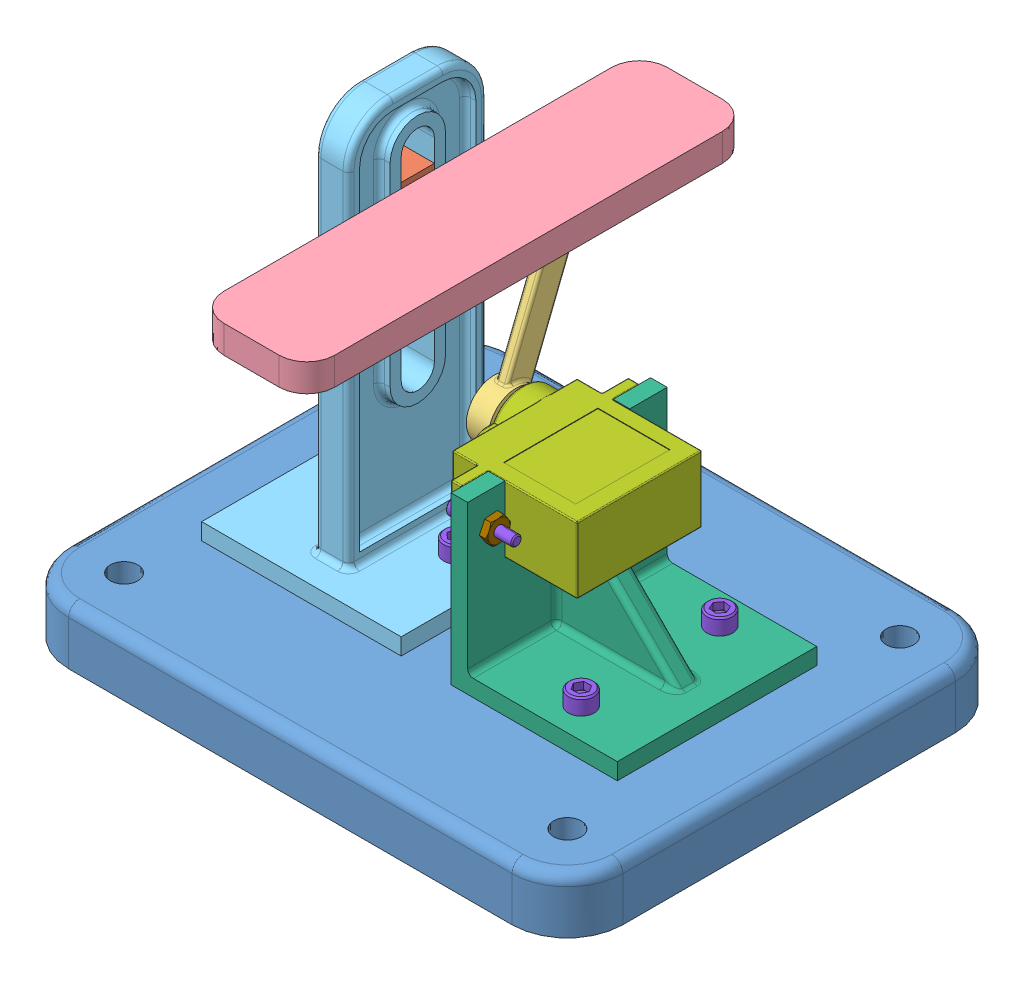
SolidWorks assembly motion_study, configuration Default. Lengths in mm.
Overall size (100 83 80).
20 component instances, 9 part files, 43 mates.
Components (placement in the parent):
- base-1: base [Default] at (53.4637 35.5858 76.1242) size (100 10 80)
- clip-1: clip [Default] at (28.4637 101.0884 76.1242) x (0 0 1) z (0 1 0) size (10 8 7)
- servo_arm-1: servo_arm [Default] at (46.9637 83.5225 65.3271) x (0 -0.929109 0.369805) z (0 -0.369805 -0.929109) size (38 4 10)
- shelf-1: shelf [Default] at (46.4637 98.5884 76.1242) x (0 0 -1) z (1 0 0) size (80 5 26)
- bracket-1: bracket [Default] at (33.4637 45.5858 76.1242) size (36 73 36)
- servo_mount-1: servo_mount [Default] at (60.4637 45.5858 76.1242) x (-1 0 0) z (0 -1 0) size (30 36 30)
- Micro Servo SG92R 180-1: Micro Servo SG92R 180 [Valor predeterminado] at (60.4637 69.5858 76.1242) x (0 0 1) z (0 -1 0) size (32 29 12)
- socket head cap screw_ai-1: socket head cap screw_ai [HX-SHCS 0.112-40x0.375x0.375-N] at (78.4637 51.4306 63.6242) x (0 -1 0) z (-0.79632 0 -0.604876) size (12.37 4.65 4.65)
- socket head cap screw_ai-2: socket head cap screw_ai [HX-SHCS 0.112-40x0.375x0.375-N] at (43.4637 51.4306 76.1242) x (0 -1 0) z (-0.276776 0 -0.960934) size (12.37 4.65 4.65)
- socket head cap screw_ai-3: socket head cap screw_ai [HX-SHCS 0.112-40x0.375x0.375-N] at (78.4637 51.4306 88.6242) x (0 -1 0) z (-0.041603 0 -0.999134) size (12.37 4.65 4.65)
- socket head cap screw_ai-4: socket head cap screw_ai [HX-SHCS 0.112-40x0.375x0.375-N] at (23.4637 51.4306 76.1242) x (0 -1 0) z (0.675067 0 0.737757) size (12.37 4.65 4.65)
- socket head cap screw_ai-5: socket head cap screw_ai [HX-SHCS 0.112-40x0.375x0.375-N] at (25.6189 101.0884 76.1242) x (1 0 0) z (0 0.700306 0.713843) size (12.37 4.65 4.65)
- machine screw nut hex_ai-1: machine screw nut hex_ai [MSHXNUT 0.112-40-S-N] at (23.4637 41.0966 76.1242) x (-0.51199 0 0.858991) z (0 -1 0) size (6.35 7.33 2.49)
- machine screw nut hex_ai-2: machine screw nut hex_ai [MSHXNUT 0.112-40-S-N] at (43.4637 43.5858 76.1242) x (-0.141311 0 -0.989965) z (0 1 0) size (6.35 7.33 2.49)
- machine screw nut hex_ai-3: machine screw nut hex_ai [MSHXNUT 0.112-40-S-N] at (78.4637 43.5858 88.6242) x (-0.491759 0 -0.870731) z (0 1 0) size (6.35 7.33 2.49)
- machine screw nut hex_ai-5: machine screw nut hex_ai [MSHXNUT 0.112-40-S-N] at (78.4637 43.5858 63.6242) x (-0.341325 0 -0.939945) z (0 1 0) size (6.35 7.33 2.49)
- machine screw nut hex_ai-6: machine screw nut hex_ai [MSHXNUT 0.073-72-S-N] at (64.7337 69.5858 89.7492) x (0 -0.430699 -0.902496) z (1 0 0) size (3.96 4.58 1.27)
- machine screw nut hex_ai-7: machine screw nut hex_ai [MSHXNUT 0.073-72-S-N] at (64.7337 69.5858 62.4992) x (0 0.064997 -0.997885) z (1 0 0) size (3.96 4.58 1.27)
- socket head cap screw_ai-7: socket head cap screw_ai [HX-SHCS 0.073-72x0.375x0.375-N] at (56.6095 69.5858 62.4992) x (1 0 0) z (0 -0.009409 0.999956) size (11.38 3 3)
- socket head cap screw_ai-8: socket head cap screw_ai [HX-SHCS 0.073-72x0.375x0.375-N] at (56.6095 69.5858 89.7492) size (11.38 3 3)
Mates (geometry in assembly coordinates):
- Coincident1: coincident anti-aligned: plane of base-1 through (53.4637 45.5858 76.1242) normal (0 1 0); plane of bracket-1 through (33.4637 45.5858 76.1242) normal (0 -1 0)
- Concentric1: concentric aligned: circle of base-1; circle of bracket-1
- Concentric2: concentric aligned: circle of base-1; circle of bracket-1
- Coincident4: coincident anti-aligned: plane of shelf-1 through (30.4637 98.5884 79.1242) normal (0 0 1); plane of bracket-1 through (-33.5363 108.5858 79.1242) normal (0 0 -1)
- Coincident5: coincident anti-aligned: plane of shelf-1 through (36.4637 103.5884 36.1242) normal (-1 0 0); plane of bracket-1 through (36.4637 118.5858 88.6242) normal (1 0 0)
- Coincident6: coincident anti-aligned: plane of clip-1 through (36.4637 103.5884 79.1242) normal (0 -1 0); plane of shelf-1 through (46.4637 103.5884 76.1242) normal (0 1 0)
- Concentric3: concentric anti-aligned: circle of clip-1; circle of shelf-1
- Coincident8: coincident anti-aligned: plane of clip-1 through (30.4637 101.0884 76.1242) normal (1 0 0); plane of bracket-1 through (30.4637 118.5858 88.6242) normal (-1 0 0)
- Coincident11: coincident anti-aligned: plane of base-1 through (53.4637 45.5858 76.1242) normal (0 1 0); plane of servo_mount-1 through (60.4637 45.5858 58.1242) normal (0 -1 0)
- Concentric8: concentric aligned: circle of base-1; circle of servo_mount-1
- Concentric9: concentric aligned: circle of base-1; circle of servo_mount-1
- Coincident14: coincident anti-aligned: plane of servo_mount-1 through (60.4637 45.5858 58.1242) normal (-1 0 0); plane of Micro Servo SG92R 180-1 through (60.4637 69.5858 89.7492) normal (1 0 0)
- Concentric10: concentric anti-aligned: circle of servo_mount-1; circle of Micro Servo SG92R 180-1
- Concentric11: concentric anti-aligned: circle of servo_mount-1; circle of Micro Servo SG92R 180-1
- Concentric12: concentric aligned: cylinder of servo_arm-1 through (44.9637 69.5858 70.8742) axis (1 0 0) radius 2.25; cylinder of Micro Servo SG92R 180-1 through (47.4637 69.5858 70.8742) axis (1 0 0) radius 2.25
- Coincident16: coincident anti-aligned: plane of bracket-1 through (33.4637 48.5858 76.1242) normal (0 1 0); plane of socket head cap screw_ai-4 through (25.1784 48.5858 74.5553) normal (0 -1 0)
- Concentric13: concentric aligned: cylinder of bracket-1 through (23.4637 45.5858 76.1242) axis (0 1 0) radius 1.5; cylinder of socket head cap screw_ai-4 through (23.4637 83.1806 76.1242) axis (0 1 0) radius 1.4224
- Coincident17: coincident anti-aligned: plane of bracket-1 through (33.4637 48.5858 76.1242) normal (0 1 0); plane of socket head cap screw_ai-2 through (41.2304 48.5858 76.7675) normal (0 -1 0)
- Concentric14: concentric aligned: cylinder of bracket-1 through (43.4637 45.5858 76.1242) axis (0 1 0) radius 1.5; cylinder of socket head cap screw_ai-2 through (43.4637 83.1806 76.1242) axis (0 1 0) radius 1.4224
- Coincident18: coincident anti-aligned: plane of servo_mount-1 through (60.4637 48.5858 58.1242) normal (0 1 0); plane of socket head cap screw_ai-3 through (76.1416 48.5858 88.7209) normal (0 -1 0)
- Concentric15: concentric aligned: cylinder of servo_mount-1 through (78.4637 33.5858 88.6242) axis (0 1 0) radius 1.5; cylinder of socket head cap screw_ai-3 through (78.4637 83.1806 88.6242) axis (0 1 0) radius 1.4224
- Coincident19: coincident anti-aligned: plane of servo_mount-1 through (60.4637 48.5858 58.1242) normal (0 1 0); plane of socket head cap screw_ai-1 through (77.0579 48.5858 65.4749) normal (0 -1 0)
- Concentric16: concentric aligned: cylinder of servo_mount-1 through (78.4637 33.5858 63.6242) axis (0 1 0) radius 1.5; cylinder of socket head cap screw_ai-1 through (78.4637 83.1806 63.6242) axis (0 1 0) radius 1.4224
- Coincident20: coincident anti-aligned: plane of clip-1 through (28.4637 101.0884 76.1242) normal (-1 0 0); plane of socket head cap screw_ai-5 through (28.4637 102.7475 74.4966) normal (1 0 0)
- Concentric17: concentric anti-aligned: circle of clip-1; cylinder of socket head cap screw_ai-5 through (-6.1311 101.0884 76.1242) axis (-1 0 0) radius 1.4224
- Coincident21: coincident anti-aligned: plane of base-1 through (53.4637 43.5858 76.1242) normal (0 -1 0); plane of machine screw nut hex_ai-1 through (26.7149 43.5858 70.6696) normal (0 1 0)
- Coincident22: coincident anti-aligned: plane of base-1 through (53.4637 43.5858 76.1242) normal (0 -1 0); plane of machine screw nut hex_ai-2 through (44.3611 43.5858 82.4105) normal (0 1 0)
- Coincident23: coincident anti-aligned: plane of base-1 through (53.4637 43.5858 76.1242) normal (0 -1 0); plane of machine screw nut hex_ai-5 through (80.6311 43.5858 69.5929) normal (0 1 0)
- Coincident24: coincident anti-aligned: plane of base-1 through (53.4637 43.5858 76.1242) normal (0 -1 0); plane of machine screw nut hex_ai-3 through (81.5864 43.5858 94.1534) normal (0 1 0)
- Concentric18: concentric anti-aligned: cylinder of socket head cap screw_ai-4 through (23.4637 83.1806 76.1242) axis (0 1 0) radius 1.4224; cylinder of machine screw nut hex_ai-1 through (23.4637 43.5858 76.1242) axis (0 -1 0) radius 1.1303
- Concentric19: concentric aligned: cylinder of socket head cap screw_ai-2 through (43.4637 83.1806 76.1242) axis (0 1 0) radius 1.4224; cylinder of machine screw nut hex_ai-2 through (43.4637 41.0966 76.1242) axis (0 1 0) radius 1.1303
- Concentric20: concentric aligned: cylinder of machine screw nut hex_ai-5 through (78.4637 41.0966 63.6242) axis (0 1 0) radius 1.1303; cylinder of socket head cap screw_ai-1 through (78.4637 83.1806 63.6242) axis (0 1 0) radius 1.4224
- Concentric21: concentric aligned: cylinder of socket head cap screw_ai-3 through (78.4637 83.1806 88.6242) axis (0 1 0) radius 1.4224; cylinder of machine screw nut hex_ai-3 through (78.4637 41.0966 88.6242) axis (0 1 0) radius 1.1303
- Coincident26: coincident anti-aligned: plane of Micro Servo SG92R 180-1 through (58.4637 69.5858 89.7492) normal (-1 0 0); plane of socket head cap screw_ai-8 through (58.4637 71.0844 89.7492) normal (1 0 0)
- Concentric22: concentric anti-aligned: cylinder of Micro Servo SG92R 180-1 through (58.4637 69.5858 89.7492) axis (1 0 0) radius 1; cylinder of socket head cap screw_ai-8 through (24.8595 69.5858 89.7492) axis (-1 0 0) radius 0.9271
- Coincident27: coincident anti-aligned: plane of Micro Servo SG92R 180-1 through (58.4637 69.5858 62.4992) normal (-1 0 0); plane of socket head cap screw_ai-7 through (58.4637 71.0844 62.5133) normal (1 0 0)
- Concentric23: concentric anti-aligned: cylinder of Micro Servo SG92R 180-1 through (58.4637 69.5858 62.4992) axis (1 0 0) radius 1; cylinder of socket head cap screw_ai-7 through (24.8595 69.5858 62.4992) axis (-1 0 0) radius 0.9271
- Coincident28: coincident anti-aligned: plane of servo_mount-1 through (63.4637 45.5858 58.1242) normal (1 0 0); plane of machine screw nut hex_ai-7 through (63.4637 69.3283 66.4532) normal (-1 0 0)
- Concentric24: concentric anti-aligned: cylinder of machine screw nut hex_ai-7 through (63.4637 69.5858 62.4992) axis (1 0 0) radius 0.7556; cylinder of socket head cap screw_ai-7 through (24.8595 69.5858 62.4992) axis (-1 0 0) radius 0.9271
- Coincident29: coincident anti-aligned: plane of servo_mount-1 through (63.4637 45.5858 58.1242) normal (1 0 0); plane of machine screw nut hex_ai-6 through (63.4637 71.2924 93.3253) normal (-1 0 0)
- Concentric25: concentric anti-aligned: cylinder of machine screw nut hex_ai-6 through (63.4637 69.5858 89.7492) axis (1 0 0) radius 0.7556; cylinder of socket head cap screw_ai-8 through (24.8595 69.5858 89.7492) axis (-1 0 0) radius 0.9271
- Distance1: distance = 1 mm anti-aligned: plane of servo_arm-1 through (48.9637 69.5858 70.8742) normal (1 0 0); plane of Micro Servo SG92R 180-1 through (49.9637 69.5858 70.8742) normal (-1 0 0)
- Concentric26: concentric anti-aligned: cylinder of clip-1 through (28.4637 82.3649 76.1242) axis (1 0 0) radius 1.425; cylinder of socket head cap screw_ai-5 through (-6.1311 82.3649 76.1242) axis (-1 0 0) radius 1.4224
